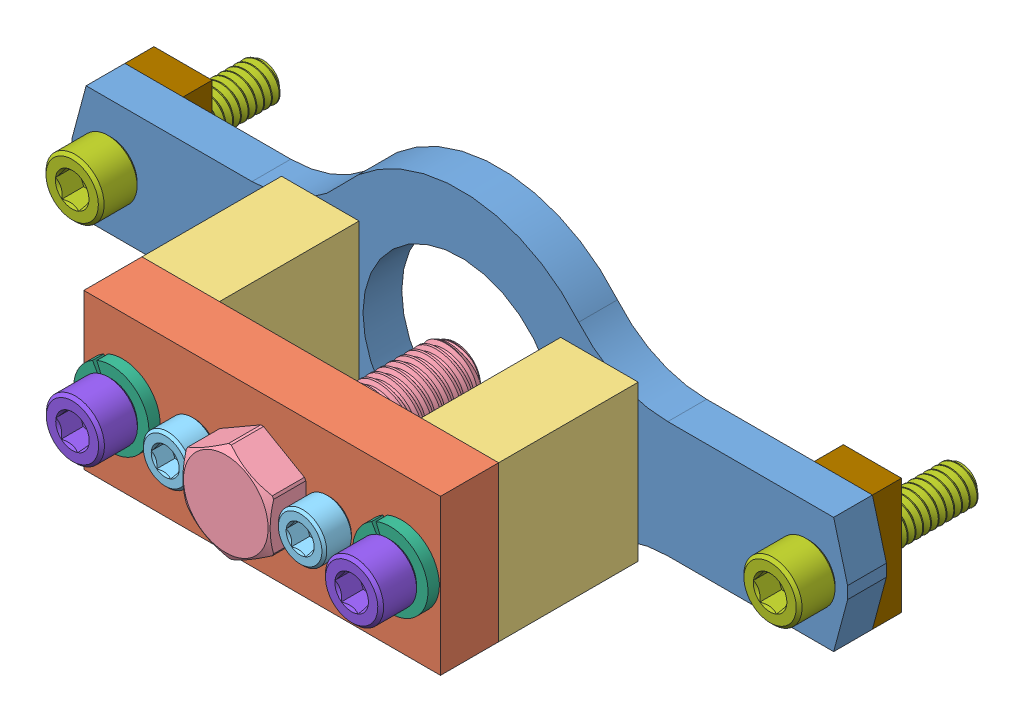
SolidWorks assembly RouseTech_Retainer_Bracket2, configuration Default. Lengths in mm.
Overall size (127 50.8 67.37).
15 component instances, 9 part files, 35 mates.
Components (placement in the parent):
- Retainment_Strap-1: Retainment_Strap [Default] at (-59.6607 23.4736 15.5345) size (127 50.8 6.35)
- RouseTech_Retaining_CrossBar2-1: RouseTech_Retaining_CrossBar2 [Default] at (33.0493 13.9486 49.507) x (0 -1 0) z (-1 0 0) size (25.4 9.53 58.42)
- Motor_Retainer_Standoff-1: Motor_Retainer_Standoff [Default] at (-19.0207 13.9486 21.8845) x (0 -1 0) z (0 0 1) size (25.4 12.7 22.86)
- Motor_Retainer_Standoff-2: Motor_Retainer_Standoff [Default] at (26.6993 13.9486 21.8845) x (0 1 0) z (0 0 1) size (25.4 12.7 22.86)
- 0.375in-16_1.25in_Bolt_MC-92620A626-1: 0.375in-16_1.25in_Bolt_MC-92620A626 [92620A626] at (3.8393 13.9486 38.3945) size (14.29 16.24 37.79)
- 10-24_0.375in_Allen_Head_Cap_Screw_MC-91251A240-1: 10-24_0.375in_Allen_Head_Cap_Screw_MC-91251A240 [91251A240] at (-7.2097 13.9486 44.7445) x (-0.923728 -0.383049 0) z (0 0 -1) size (7.92 7.92 15.51)
- 10-24_0.375in_Allen_Head_Cap_Screw_MC-91251A240-2: 10-24_0.375in_Allen_Head_Cap_Screw_MC-91251A240 [91251A240] at (14.8883 13.9486 44.7445) x (-0.923728 -0.383049 0) z (0 0 -1) size (7.92 7.92 15.51)
- 0.25in_Lock_Washer-1: 0.25in_Lock_Washer [Default] at (26.6993 13.9486 56.1237) x (-0.923728 -0.383049 0) z (0 0 -1) size (12.32 12.32 1.85)
- 0.25in_Lock_Washer-2: 0.25in_Lock_Washer [Default] at (-19.0207 13.9486 56.1237) x (-0.923728 -0.383049 0) z (0 0 -1) size (12.32 12.32 1.85)
- 0.25-20_1.0in_Allen Head_Cap_Screw_MC-91251A542-1: 0.25-20_1.0in_Allen Head_Cap_Screw_MC-91251A542 [91251A542] at (60.9893 13.9486 -3.5155) x (-0.923728 -0.383049 0) z (0 0 -1) size (9.53 9.53 33.14)
- 0.25-20_1.0in_Allen Head_Cap_Screw_MC-91251A542-2: 0.25-20_1.0in_Allen Head_Cap_Screw_MC-91251A542 [91251A542] at (-53.3107 13.9486 -3.5155) x (-0.923728 -0.383049 0) z (0 0 -1) size (9.53 9.53 33.14)
- 0.25-20_1.75in_Allen Head_Cap_Screw_MC-91251A548-1: 0.25-20_1.75in_Allen Head_Cap_Screw_MC-91251A548 [91251A548] at (26.6993 13.9486 11.6737) x (-0.923728 -0.383049 0) z (0 0 -1) size (9.53 9.53 52.19)
- 0.25-20_1.75in_Allen Head_Cap_Screw_MC-91251A548-2: 0.25-20_1.75in_Allen Head_Cap_Screw_MC-91251A548 [91251A548] at (-19.0207 13.9486 11.6737) x (-0.950943 -0.309366 0) z (0 0 -1) size (9.53 9.53 52.19)
- RouseTech_Retainer_Spacer-1: RouseTech_Retainer_Spacer [Default] at (60.2908 13.9486 10.772) x (0 -1 0) z (0 0 1) size (19.05 9.53 4.76)
- RouseTech_Retainer_Spacer-2: RouseTech_Retainer_Spacer [Default] at (-52.6122 13.9486 10.772) x (0 1 0) z (0 0 1) size (19.05 9.53 4.76)
Mates (geometry in assembly coordinates):
- Coincident1: coincident anti-aligned: axis of Retainment_Strap-1 through (3.8393 13.9486 21.8845) axis (0 0 -1); axis of RouseTech_Retaining_CrossBar2-1 through (3.8393 13.9486 44.7445) axis (0 0 1)
- Parallel1: parallel aligned: plane of Retainment_Strap-1 through (27.3857 23.4736 21.8845) normal (0 1 0); plane of RouseTech_Retaining_CrossBar2-1 through (-25.3707 26.6486 44.7445) normal (0 1 0)
- Coincident3: coincident aligned: axis of RouseTech_Retaining_CrossBar2-1 through (-19.0207 13.9486 44.7445) axis (0 0 1); axis of Motor_Retainer_Standoff-1 through (-19.0207 13.9486 21.8845) axis (0 0 1)
- Coincident4: coincident anti-aligned: plane of RouseTech_Retaining_CrossBar2-1 through (-25.3707 26.6486 44.7445) normal (0 0 -1); plane of Motor_Retainer_Standoff-1 through (-12.6707 1.2486 44.7445) normal (0 0 1)
- Parallel2: parallel anti-aligned: plane of RouseTech_Retaining_CrossBar2-1 through (-25.3707 1.2486 54.2695) normal (-1 0 0); plane of Motor_Retainer_Standoff-1 through (-12.6707 26.6486 44.7445) normal (1 0 0)
- Coincident6: coincident aligned: axis of RouseTech_Retaining_CrossBar2-1 through (26.6993 13.9486 44.7445) axis (0 0 1); axis of Motor_Retainer_Standoff-2 through (26.6993 13.9486 21.8845) axis (0 0 1)
- Coincident7: coincident anti-aligned: plane of RouseTech_Retaining_CrossBar2-1 through (-25.3707 26.6486 44.7445) normal (0 0 -1); plane of Motor_Retainer_Standoff-2 through (20.3493 26.6486 44.7445) normal (0 0 1)
- Parallel3: parallel aligned: plane of RouseTech_Retaining_CrossBar2-1 through (33.0493 1.2486 54.2695) normal (1 0 0); plane of Motor_Retainer_Standoff-2 through (33.0493 1.2486 44.7445) normal (1 0 0)
- Coincident9: coincident anti-aligned: plane of Retainment_Strap-1 through (3.8393 13.9486 21.8845) normal (0 0 1); plane of Motor_Retainer_Standoff-2 through (20.3493 26.6486 21.8845) normal (0 0 -1)
- Coincident10: coincident anti-aligned: plane of RouseTech_Retaining_CrossBar2-1 through (-25.3707 26.6486 54.2695) normal (0 0 1); plane of 0.375in-16_1.25in_Bolt_MC-92620A626-1 through (10.983 18.0731 54.2695) normal (0 0 -1)
- Coincident11: coincident anti-aligned: axis of RouseTech_Retaining_CrossBar2-1 through (3.8393 13.9486 44.7445) axis (0 0 1); axis of 0.375in-16_1.25in_Bolt_MC-92620A626-1 through (3.8393 13.9486 59.5342) axis (0 0 -1)
- Coincident12: coincident anti-aligned: plane of RouseTech_Retaining_CrossBar2-1 through (-25.3707 26.6486 54.2695) normal (0 0 1); plane of 10-24_0.375in_Allen_Head_Cap_Screw_MC-91251A240-2 through (14.8883 13.9486 54.2695) normal (0 0 -1)
- Coincident13: coincident anti-aligned: axis of RouseTech_Retaining_CrossBar2-1 through (14.8883 13.9486 44.7445) axis (0 0 1); axis of 10-24_0.375in_Allen_Head_Cap_Screw_MC-91251A240-2 through (14.8883 13.9486 58.6993) axis (0 0 -1)
- Coincident14: coincident anti-aligned: plane of 10-24_0.375in_Allen_Head_Cap_Screw_MC-91251A240-1 through (-7.2097 13.9486 54.2695) normal (0 0 -1); plane of RouseTech_Retaining_CrossBar2-1 through (-25.3707 26.6486 54.2695) normal (0 0 1)
- Coincident15: coincident anti-aligned: axis of RouseTech_Retaining_CrossBar2-1 through (-7.2097 13.9486 44.7445) axis (0 0 1); axis of 10-24_0.375in_Allen_Head_Cap_Screw_MC-91251A240-1 through (-7.2097 13.9486 58.6993) axis (0 0 -1)
- Coincident21: coincident anti-aligned: plane of RouseTech_Retaining_CrossBar2-1 through (-25.3707 26.6486 54.2695) normal (0 0 1); plane of 0.25in_Lock_Washer-1 through (26.6993 13.9486 54.2695) normal (0 0 -1)
- Coincident22: coincident anti-aligned: plane of RouseTech_Retaining_CrossBar2-1 through (-25.3707 26.6486 54.2695) normal (0 0 1); plane of 0.25in_Lock_Washer-2 through (-19.0207 13.9486 54.2695) normal (0 0 -1)
- Coincident24: coincident anti-aligned: axis of Retainment_Strap-1 through (-53.3107 13.9486 15.5345) axis (0 0 1); axis of 0.25-20_1.0in_Allen Head_Cap_Screw_MC-91251A542-2 through (-53.3107 13.9486 27.7583) axis (0 0 -1)
- Coincident25: coincident anti-aligned: plane of Retainment_Strap-1 through (3.8393 13.9486 21.8845) normal (0 0 1); plane of 0.25-20_1.0in_Allen Head_Cap_Screw_MC-91251A542-2 through (-53.3107 13.9486 21.8845) normal (0 0 -1)
- Coincident26: coincident anti-aligned: axis of Retainment_Strap-1 through (60.9893 13.9486 15.5345) axis (0 0 1); axis of 0.25-20_1.0in_Allen Head_Cap_Screw_MC-91251A542-1 through (60.9893 13.9486 27.7583) axis (0 0 -1)
- Coincident27: coincident anti-aligned: plane of Retainment_Strap-1 through (3.8393 13.9486 21.8845) normal (0 0 1); plane of 0.25-20_1.0in_Allen Head_Cap_Screw_MC-91251A542-1 through (60.9893 13.9486 21.8845) normal (0 0 -1)
- Coincident28: coincident anti-aligned: plane of RouseTech_Retaining_CrossBar2-1 through (-25.3707 26.6486 54.2695) normal (0 0 1); plane of 0.25in_Lock_Washer-1 through (26.6993 13.9486 54.2695) normal (0 0 -1)
- Coincident29: coincident aligned: axis of RouseTech_Retaining_CrossBar2-1 through (26.6993 13.9486 44.7445) axis (0 0 1); axis of 0.25in_Lock_Washer-1 through (26.6993 13.9486 54.2695) axis (0 0 1)
- Coincident30: coincident anti-aligned: plane of RouseTech_Retaining_CrossBar2-1 through (-25.3707 26.6486 54.2695) normal (0 0 1); circle of 0.25in_Lock_Washer-2
- Coincident31: coincident aligned: axis of RouseTech_Retaining_CrossBar2-1 through (-19.0207 13.9486 44.7445) axis (0 0 1); axis of 0.25in_Lock_Washer-2 through (-19.0207 13.9486 54.2695) axis (0 0 1)
- Coincident32: coincident anti-aligned: axis of 0.25-20_1.75in_Allen Head_Cap_Screw_MC-91251A548-2 through (-19.0207 13.9486 56.1237) axis (0 0 -1); axis of RouseTech_Retaining_CrossBar2-1 through (-19.0207 13.9486 44.7445) axis (0 0 1)
- Coincident33: coincident anti-aligned: plane of 0.25in_Lock_Washer-2 through (-19.0207 13.9486 56.1237) normal (0 0 1); plane of 0.25-20_1.75in_Allen Head_Cap_Screw_MC-91251A548-2 through (-19.0207 13.9486 56.1237) normal (0 0 -1)
- Coincident34: coincident anti-aligned: plane of 0.25in_Lock_Washer-1 through (26.6993 13.9486 56.1237) normal (0 0 1); plane of 0.25-20_1.75in_Allen Head_Cap_Screw_MC-91251A548-1 through (26.6993 13.9486 56.1237) normal (0 0 -1)
- Coincident35: coincident anti-aligned: axis of RouseTech_Retaining_CrossBar2-1 through (26.6993 13.9486 44.7445) axis (0 0 1); axis of 0.25-20_1.75in_Allen Head_Cap_Screw_MC-91251A548-1 through (26.6993 13.9486 56.1237) axis (0 0 -1)
- Coincident36: coincident aligned: axis of Retainment_Strap-1 through (60.9893 13.9486 15.5345) axis (0 0 1); axis of RouseTech_Retainer_Spacer-1 through (60.9893 13.9486 10.772) axis (0 0 1)
- Coincident37: coincident aligned: plane of Retainment_Strap-1 through (67.3393 4.4236 21.8845) normal (0 -1 0); plane of RouseTech_Retainer_Spacer-1 through (55.5283 4.4236 15.5345) normal (0 -1 0)
- Coincident38: coincident anti-aligned: plane of Retainment_Strap-1 through (3.8393 13.9486 15.5345) normal (0 0 -1); plane of RouseTech_Retainer_Spacer-1 through (65.0533 4.4236 15.5345) normal (0 0 1)
- Coincident39: coincident aligned: axis of Retainment_Strap-1 through (-53.3107 13.9486 15.5345) axis (0 0 1); axis of RouseTech_Retainer_Spacer-2 through (-53.3107 13.9486 10.772) axis (0 0 1)
- Coincident40: coincident aligned: plane of Retainment_Strap-1 through (-59.6607 4.4236 21.8845) normal (0 -1 0); plane of RouseTech_Retainer_Spacer-2 through (-47.8497 4.4236 15.5345) normal (0 -1 0)
- Coincident41: coincident anti-aligned: plane of Retainment_Strap-1 through (3.8393 13.9486 15.5345) normal (0 0 -1); plane of RouseTech_Retainer_Spacer-2 through (-57.3747 23.4736 15.5345) normal (0 0 1)
